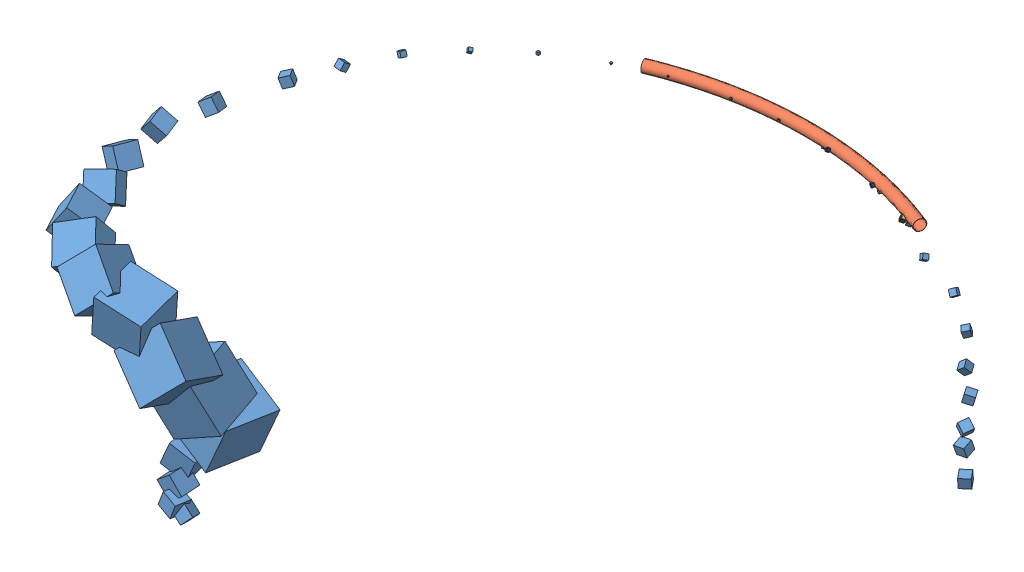
SolidWorks assembly tube3A, configuration Default. Lengths in mm.
Overall size (6090.6 175.44 943.44).
80 component instances, 74 part files, 16 mates.
Components (placement in the parent):
- cube_positions-1: cube_positions [Default] at (-2670.6643 -3280.6684 6355.7547) x (0.67216 -0.00431 -0.740393) z (0.73275 0.147305 0.664364) size (10173.18 3894.08 5705.72) (hidden)
- tubes-1: tubes [tube3A] at origin size (6090.6 168.28 943.44)
- cube_09-1: cube_09 [cube09] at (1891.328 -39.9576 -219.9855) x (0.558213 -0.291956 0.776634) z (-0.686222 0.363684 0.629947) size (66.67 66.67 66.67)
  - panel_R^cube_09-13: panel_R^cube_09 [cube01] x (-1 0 0) z (0 0 1) size (50.8 1.59 50.8) (virtual)
  - acrylic_R^cube_09-1: acrylic_R^cube_09 [A] at origin size (63.4 3.23 63.4) (virtual)
  - panel_O^cube_09-8: panel_O^cube_09 [cube01] x (0 -1 0) z (0 0 1) size (50.8 1.59 50.8) (virtual)
  - acrylic_O^cube_09-23: acrylic_O^cube_09 [A] x (0 1 0) z (0 0 1) size (63.4 3.23 63.4) (virtual)
  - panel_Y^cube_09-9: panel_Y^cube_09 [cube01] at origin size (50.8 1.59 50.8) (virtual)
  - acrylic_Y^cube_09-24: acrylic_Y^cube_09 [A] x (-1 0 0) z (0 0 1) size (63.4 3.23 63.4) (virtual)
  - panel_G^cube_09-10: panel_G^cube_09 [cube01] x (0 1 0) z (0 0 1) size (50.8 1.59 50.8) (virtual)
  - acrylic_G^cube_09-25: acrylic_G^cube_09 [A] x (0 -1 0) z (0 0 1) size (63.4 3.23 63.4) (virtual)
  - panel_C^cube_09-11: panel_C^cube_09 [cube01] x (-1 0 0) z (0 -1 0) size (50.8 1.59 50.8) (virtual)
  - acrylic_C^cube_09-26: acrylic_C^cube_09 [B] x (1 0 0) z (0 -1 0) size (63.4 3.23 63.4) (virtual)
  - panel_B^cube_09-13: panel_B^cube_09 [cube01] x (-1 0 0) z (0 1 0) size (50.8 1.59 50.8) (virtual)
  - acrylic_B^cube_09-27: acrylic_B^cube_09 [B] x (1 0 0) z (0 1 0) size (63.4 3.23 63.4) (virtual)
- cube_10-1: cube_10 [cube10] at (1228.5614 -17.4711 -418.2438) x (-0.71669 -0.609869 -0.338254) z (-0.59783 0.78702 -0.152311) size (53.98 53.98 53.98)
  - panel_R^cube_10-13: panel_R^cube_10 [cube01] x (-1 0 0) z (0 0 1) size (40.64 1.59 40.64) (virtual)
  - acrylic_R^cube_10-1: acrylic_R^cube_10 [A] at origin size (50.7 3.23 50.7) (virtual)
  - panel_O^cube_10-8: panel_O^cube_10 [cube01] x (0 -1 0) z (0 0 1) size (40.64 1.59 40.64) (virtual)
  - acrylic_O^cube_10-23: acrylic_O^cube_10 [A] x (0 1 0) z (0 0 1) size (50.7 3.23 50.7) (virtual)
  - panel_Y^cube_10-9: panel_Y^cube_10 [cube01] at origin size (40.64 1.59 40.64) (virtual)
  - acrylic_Y^cube_10-24: acrylic_Y^cube_10 [A] x (-1 0 0) z (0 0 1) size (50.7 3.23 50.7) (virtual)
  - panel_G^cube_10-10: panel_G^cube_10 [cube01] x (0 1 0) z (0 0 1) size (40.64 1.59 40.64) (virtual)
  - acrylic_G^cube_10-25: acrylic_G^cube_10 [A] x (0 -1 0) z (0 0 1) size (50.7 3.23 50.7) (virtual)
  - panel_C^cube_10-11: panel_C^cube_10 [cube01] x (-1 0 0) z (0 -1 0) size (40.64 1.59 40.64) (virtual)
  - acrylic_C^cube_10-26: acrylic_C^cube_10 [B] x (1 0 0) z (0 -1 0) size (50.7 3.23 50.7) (virtual)
  - panel_B^cube_10-13: panel_B^cube_10 [cube01] x (-1 0 0) z (0 1 0) size (40.64 1.59 40.64) (virtual)
  - acrylic_B^cube_10-27: acrylic_B^cube_10 [B] x (1 0 0) z (0 1 0) size (50.7 3.23 50.7) (virtual)
- cube_11-1: cube_11 [cube11] at (417.5304 -1.7159 -528.0192) x (0.316006 -0.604945 0.730877) z (0.798081 0.586057 0.140015) size (46.35 46.35 46.35)
  - panel_R^cube_11-13: panel_R^cube_11 [cube01] x (-1 0 0) z (0 0 1) size (34.54 1.59 34.54) (virtual)
  - acrylic_R^cube_11-1: acrylic_R^cube_11 [A] at origin size (43.08 3.23 43.08) (virtual)
  - panel_O^cube_11-8: panel_O^cube_11 [cube01] x (0 -1 0) z (0 0 1) size (34.54 1.59 34.54) (virtual)
  - acrylic_O^cube_11-23: acrylic_O^cube_11 [A] x (0 1 0) z (0 0 1) size (43.08 3.23 43.08) (virtual)
  - panel_Y^cube_11-9: panel_Y^cube_11 [cube01] at origin size (34.54 1.59 34.54) (virtual)
  - acrylic_Y^cube_11-24: acrylic_Y^cube_11 [A] x (-1 0 0) z (0 0 1) size (43.08 3.23 43.08) (virtual)
  - panel_G^cube_11-10: panel_G^cube_11 [cube01] x (0 1 0) z (0 0 1) size (34.54 1.59 34.54) (virtual)
  - acrylic_G^cube_11-25: acrylic_G^cube_11 [A] x (0 -1 0) z (0 0 1) size (43.08 3.23 43.08) (virtual)
  - panel_C^cube_11-11: panel_C^cube_11 [cube01] x (-1 0 0) z (0 -1 0) size (34.54 1.59 34.54) (virtual)
  - acrylic_C^cube_11-26: acrylic_C^cube_11 [B] x (1 0 0) z (0 -1 0) size (43.08 3.23 43.08) (virtual)
  - panel_B^cube_11-13: panel_B^cube_11 [cube01] x (-1 0 0) z (0 1 0) size (34.54 1.59 34.54) (virtual)
  - acrylic_B^cube_11-27: acrylic_B^cube_11 [B] x (1 0 0) z (0 1 0) size (43.08 3.23 43.08) (virtual)
- cube_12-1: cube_12 [cube12] at (-358.2393 3.7306 -535.1453) x (0.586492 0.345764 0.732445) z (-0.809811 0.233265 0.538324) size (33.65 33.65 33.65)
  - panel_R^cube_12-13: panel_R^cube_12 [cube01] x (-1 0 0) z (0 0 1) size (24.38 1.59 24.38) (virtual)
  - acrylic_R^cube_12-1: acrylic_R^cube_12 [A] at origin size (30.38 3.23 30.38) (virtual)
  - panel_O^cube_12-8: panel_O^cube_12 [cube01] x (0 -1 0) z (0 0 1) size (24.38 1.59 24.38) (virtual)
  - acrylic_O^cube_12-23: acrylic_O^cube_12 [A] x (0 1 0) z (0 0 1) size (30.38 3.23 30.38) (virtual)
  - panel_Y^cube_12-9: panel_Y^cube_12 [cube01] at origin size (24.38 1.59 24.38) (virtual)
  - acrylic_Y^cube_12-24: acrylic_Y^cube_12 [A] x (-1 0 0) z (0 0 1) size (30.38 3.23 30.38) (virtual)
  - panel_G^cube_12-10: panel_G^cube_12 [cube01] x (0 1 0) z (0 0 1) size (24.38 1.59 24.38) (virtual)
  - acrylic_G^cube_12-25: acrylic_G^cube_12 [A] x (0 -1 0) z (0 0 1) size (30.38 3.23 30.38) (virtual)
  - panel_C^cube_12-11: panel_C^cube_12 [cube01] x (-1 0 0) z (0 -1 0) size (24.38 1.59 24.38) (virtual)
  - acrylic_C^cube_12-26: acrylic_C^cube_12 [B] x (1 0 0) z (0 -1 0) size (30.38 3.23 30.38) (virtual)
  - panel_B^cube_12-13: panel_B^cube_12 [cube01] x (-1 0 0) z (0 1 0) size (24.38 1.59 24.38) (virtual)
  - acrylic_B^cube_12-27: acrylic_B^cube_12 [B] x (1 0 0) z (0 1 0) size (30.38 3.23 30.38) (virtual)
- cube_13-1: cube_13 [cube13] at (-1020.6914 4.0423 -454.5155) x (0.910611 -0.27141 0.311647) z (0.00891 0.76683 0.641789) size (28.57 28.57 28.57)
  - panel_R^cube_13-13: panel_R^cube_13 [cube01] x (-1 0 0) z (0 0 1) size (20.32 1.59 20.32) (virtual)
  - acrylic_R^cube_13-1: acrylic_R^cube_13 [A] at origin size (25.3 3.23 25.3) (virtual)
  - panel_O^cube_13-8: panel_O^cube_13 [cube01] x (0 -1 0) z (0 0 1) size (20.32 1.59 20.32) (virtual)
  - acrylic_O^cube_13-23: acrylic_O^cube_13 [A] x (0 1 0) z (0 0 1) size (25.3 3.23 25.3) (virtual)
  - panel_Y^cube_13-9: panel_Y^cube_13 [cube01] at origin size (20.32 1.59 20.32) (virtual)
  - acrylic_Y^cube_13-24: acrylic_Y^cube_13 [A] x (-1 0 0) z (0 0 1) size (25.3 3.23 25.3) (virtual)
  - panel_G^cube_13-10: panel_G^cube_13 [cube01] x (0 1 0) z (0 0 1) size (20.32 1.59 20.32) (virtual)
  - acrylic_G^cube_13-25: acrylic_G^cube_13 [A] x (0 -1 0) z (0 0 1) size (25.3 3.23 25.3) (virtual)
  - panel_C^cube_13-11: panel_C^cube_13 [cube01] x (-1 0 0) z (0 -1 0) size (20.32 1.59 20.32) (virtual)
  - acrylic_C^cube_13-26: acrylic_C^cube_13 [B] x (1 0 0) z (0 -1 0) size (25.3 3.23 25.3) (virtual)
  - panel_B^cube_13-13: panel_B^cube_13 [cube01] x (-1 0 0) z (0 1 0) size (20.32 1.59 20.32) (virtual)
  - acrylic_B^cube_13-27: acrylic_B^cube_13 [B] x (1 0 0) z (0 1 0) size (25.3 3.23 25.3) (virtual)
- cube_14-1: cube_14 [cube14] at (-1799.1926 16.7711 -254.42) x (0.802946 -0.45597 -0.383887) z (0.528044 0.2454 0.812987) size (20.96 20.96 20.96)
  - panel_R^cube_14-13: panel_R^cube_14 [cube01] x (-1 0 0) z (0 0 1) size (14.22 1.59 14.22) (virtual)
  - acrylic_R^cube_14-1: acrylic_R^cube_14 [A] at origin size (17.68 3.23 17.68) (virtual)
  - panel_O^cube_14-8: panel_O^cube_14 [cube01] x (0 -1 0) z (0 0 1) size (14.22 1.59 14.22) (virtual)
  - acrylic_O^cube_14-23: acrylic_O^cube_14 [A] x (0 1 0) z (0 0 1) size (17.68 3.23 17.68) (virtual)
  - panel_Y^cube_14-9: panel_Y^cube_14 [cube01] at origin size (14.22 1.59 14.22) (virtual)
  - acrylic_Y^cube_14-24: acrylic_Y^cube_14 [A] x (-1 0 0) z (0 0 1) size (17.68 3.23 17.68) (virtual)
  - panel_G^cube_14-10: panel_G^cube_14 [cube01] x (0 1 0) z (0 0 1) size (14.22 1.59 14.22) (virtual)
  - acrylic_G^cube_14-25: acrylic_G^cube_14 [A] x (0 -1 0) z (0 0 1) size (17.68 3.23 17.68) (virtual)
  - panel_C^cube_14-11: panel_C^cube_14 [cube01] x (-1 0 0) z (0 -1 0) size (14.22 1.59 14.22) (virtual)
  - acrylic_C^cube_14-26: acrylic_C^cube_14 [B] x (1 0 0) z (0 -1 0) size (17.68 3.23 17.68) (virtual)
  - panel_B^cube_14-13: panel_B^cube_14 [cube01] x (-1 0 0) z (0 1 0) size (14.22 1.59 14.22) (virtual)
  - acrylic_B^cube_14-27: acrylic_B^cube_14 [B] x (1 0 0) z (0 1 0) size (17.68 3.23 17.68) (virtual)
Mates (geometry in assembly coordinates):
- Coincident1: coincident aligned: plane of cube_positions-1 through (1952.5635 -154.6666 -280.8611) normal (0.686222 -0.363684 -0.629947); plane of cube_09-1/panel_B^cube_09-13 through (1949.3113 -150.1135 -287.0323) normal (0.686222 -0.363684 -0.629947)
- Coincident2: coincident aligned: plane of cube_positions-1 through (1910.5222 -132.3856 -242.2675) normal (0.558213 -0.291956 0.776634); plane of cube_09-1/panel_G^cube_09-10 through (1948.2953 -149.5442 -275.8676) normal (0.558213 -0.291956 0.776634)
- Coincident3: coincident aligned: plane of cube_positions-1 through (1904.8952 -60.3048 -290.0111) normal (0.466366 0.884588 -0.002666); plane of cube_09-1/panel_R^cube_09-13 through (1971.2576 -95.2683 -282.1887) normal (0.466366 0.884588 -0.002666)
- Coincident13: coincident aligned: plane of cube_positions-1 through (310.08 -40.063 -555.0274) normal (0.798081 0.586057 0.140015); plane of cube_11-1/panel_C^cube_11-11 through (328.9659 -58.2949 -586.3636) normal (0.798081 0.586057 0.140015)
- Coincident14: coincident aligned: plane of cube_positions-1 through (279.9164 -62.2132 -560.3193) normal (-0.513037 0.539053 0.667993); plane of cube_11-1/panel_Y^cube_11-9 through (265.0157 -39.299 -590.2545) normal (-0.513037 0.539053 0.667993)
- Coincident15: coincident aligned: plane of cube_positions-1 through (279.9164 -62.2132 -560.3193) normal (0.316006 -0.604945 0.730877); plane of cube_11-1/panel_G^cube_11-10 through (280.8278 -66.9521 -564.6358) normal (0.316006 -0.604945 0.730877)
- Coincident16: coincident aligned: plane of cube_positions-1 through (-361.991 -26.3767 -569.4866) normal (-0.809811 0.233265 0.538324); plane of cube_12-1/panel_C^cube_12-11 through (-365.0766 -6.1525 -582.8918) normal (-0.809811 0.233265 0.538324)
- Coincident17: coincident aligned: plane of cube_positions-1 through (-362.4288 -0.3367 -581.4287) normal (-0.015279 0.908864 -0.416812); plane of cube_12-1/panel_R^cube_12-13 through (-341.6471 -8.7087 -600.4459) normal (-0.015279 0.908864 -0.416812)
- Coincident18: coincident aligned: plane of cube_positions-1 through (-361.991 -26.3767 -569.4866) normal (0.586492 0.345764 0.732445); plane of cube_12-1/panel_G^cube_12-10 through (-338.4851 -33.4807 -584.955) normal (0.586492 0.345764 0.732445)
- Coincident25: coincident aligned: plane of cube_positions-1 through (-1038.7638 -16.3289 -494.2964) normal (-0.00891 -0.76683 -0.641789); plane of cube_13-1/panel_B^cube_13-13 through (-1014.7963 -20.5635 -489.5696) normal (-0.00891 -0.76683 -0.641789)
- Coincident26: coincident aligned: plane of cube_positions-1 through (-1019.4252 -5.9096 -474.2445) normal (-0.413168 -0.581643 0.700702); plane of cube_13-1/panel_Y^cube_13-9 through (-1034.9685 -14.2841 -490.3611) normal (-0.413168 -0.581643 0.700702)
- Coincident30: coincident aligned: plane of cube_positions-1 through (1297.4563 -51.1161 -432.1099) normal (0.71669 0.609869 0.338254); plane of cube_10-1/panel_O^cube_10-8 through (1325.3096 -83.5544 -432.6395) normal (0.71669 0.609869 0.338254)
- Coincident31: coincident aligned: plane of cube_positions-1 through (1291.6597 -119.2396 -441.178) normal (0.59783 -0.78702 0.152311); plane of cube_10-1/panel_B^cube_10-13 through (1309.9848 -113.8713 -485.3661) normal (0.59783 -0.78702 0.152311)
- Coincident34: coincident aligned: plane of cube_positions-1 through (-1803.4939 5.8466 -279.6942) normal (0.528044 0.2454 0.812987); plane of cube_14-1/panel_C^cube_14-11 through (-1786.555 14.0369 -293.1685) normal (0.528044 0.2454 0.812987)
- Coincident35: coincident aligned: plane of cube_positions-1 through (-1812.2937 1.7571 -293.2425) normal (-0.276492 -0.855494 0.437815); plane of ? through (-1812.1274 1.1585 -294.3072) normal (-0.276492 -0.855494 0.437815)
- Sketch4: unknown = 59.7758 mm: unknown of ?; unknown of cube_12-1/acrylic_B^cube_12-27; unknown of cube_14-1/panel_B^cube_14-13; unknown of cube_09-1/acrylic_B^cube_09-27; unknown of cube_09-1/acrylic_B^cube_09-27; unknown of cube_10-1/acrylic_B^cube_10-27; unknown of cube_10-1/acrylic_B^cube_10-27; unknown of ?; unknown of ?; unknown of ?; unknown of cube_14-1/acrylic_B^cube_14-27; unknown of tubes-1
